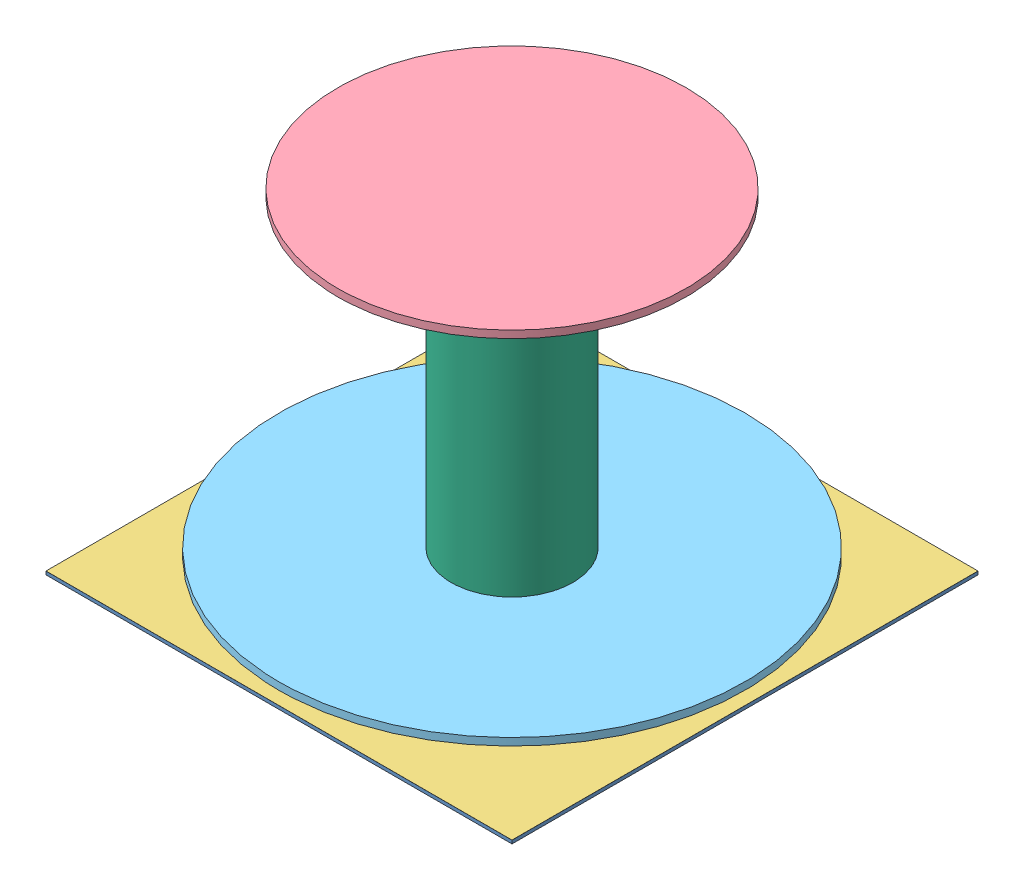
SolidWorks assembly Assem3, configuration Default. Lengths in mm.
Overall size (80.3 57.75 80.3).
6 component instances, 6 part files, 10 mates.
Components (placement in the parent):
- Dielectric Three Eighths-1: Dielectric Three Eighths [Default] at (-61.9996 46.8196 131.861) size (80.3 0.57 80.3)
- Feed Network Three Eighths-1: Feed Network Three Eighths [Default] at (-59.855 46.8974 74.0785) size (72.65 0.01 32.24)
- Ground Plane Three Eighths-1: Ground Plane Three Eighths [Default] at (-61.8734 47.4839 131.7348) size (80.3 0.01 80.3)
- Parasitic SAP Three Eighths-1: Parasitic SAP Three Eighths [Default] at (-8.4646 103.1624 78.326) size (60 1.28 60)
- SAP Three Eighths-1: SAP Three Eighths [Default] at (-8.4646 49.5389 78.326) size (80.3 1.28 80.3)
- Tower Three Eighths-1: Tower Three Eighths [Default] at (-8.4646 38.1891 78.326) size (21 55.87 21)
Mates (geometry in assembly coordinates):
- Coincident1: coincident: point of Dielectric Three Eighths-1; point of Ground Plane Three Eighths-1
- Coincident5: coincident anti-aligned: plane of Parasitic SAP Three Eighths-1 through (-8.4646 103.3749 78.326) normal (0 -1 0); plane of Tower Three Eighths-1 through (-8.4646 103.3749 78.326) normal (0 1 0)
- Concentric1: concentric aligned: circle of Parasitic SAP Three Eighths-1; circle of Tower Three Eighths-1
- Distance3: distance = 2.25 mm aligned: plane of SAP Three Eighths-1 through (-8.4646 49.7514 78.326) normal (0 -1 0); plane of Tower Three Eighths-1 through (-8.4646 47.5014 78.326) normal (0 -1 0)
- Concentric2: concentric aligned: circle of SAP Three Eighths-1; circle of Tower Three Eighths-1
- Coincident7: coincident anti-aligned: plane of Ground Plane Three Eighths-1 through (-48.6158 47.5014 118.4773) normal (0 1 0); plane of Tower Three Eighths-1 through (-8.4646 47.5014 78.326) normal (0 -1 0)
- Concentric3: concentric anti-aligned: circle of Ground Plane Three Eighths-1; circle of Tower Three Eighths-1
- Coincident9: coincident: plane of Dielectric Three Eighths-1 through (-48.6158 46.9149 118.4773) normal (0 -1 0); plane of Feed Network Three Eighths-1 through (-48.6158 46.9149 73.0723) normal (0 1 0)
- Distance5: distance = 33.3975 mm: point of Feed Network Three Eighths-1; point of Dielectric Three Eighths-1
- Coincident11: coincident aligned: line of Dielectric Three Eighths-1 through (-48.6158 46.9149 38.1748) axis (0 0 1); line of Feed Network Three Eighths-1 through (-48.6158 46.9149 71.5723) axis (0 0 1)
